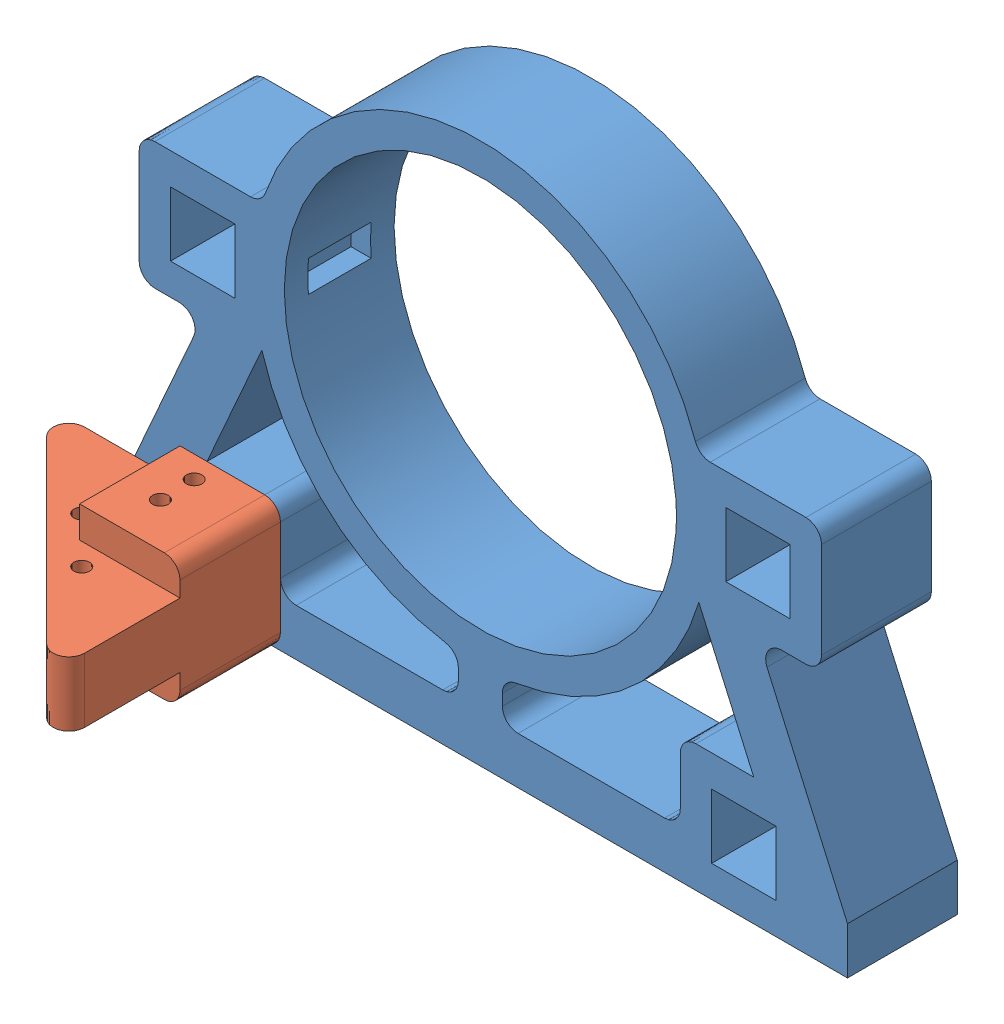
SolidWorks assembly deneme., configuration Varsayılan. Lengths in mm.
Overall size (248.14 172.66 102.43).
2 component instances, 2 part files, 3 mates.
Components (placement in the parent):
- auv_on-1: auv_on [Varsayılan] at (-15.7031 25.421 216.5) size (234 172.66 35)
- motortutucuon_ters-1: motortutucuon_ters [Varsayılan] at (-106.1133 -64.7403 269.6272) x (1 0 0) z (0 1 0) size (67.43 67.43 40.5)
Mates (geometry in assembly coordinates):
- Coincident2: coincident: point of assembly; point of assembly; moEndPointRef_w of auv_on-1; moEndPointRef_w of motortutucuon_ters-1
- Coincident3: coincident: point of assembly; point of assembly; moEndPointRef_w of auv_on-1; moEndPointRef_w of motortutucuon_ters-1
- Coincident4: coincident: unknown of auv_on-1; unknown of motortutucuon_ters-1
